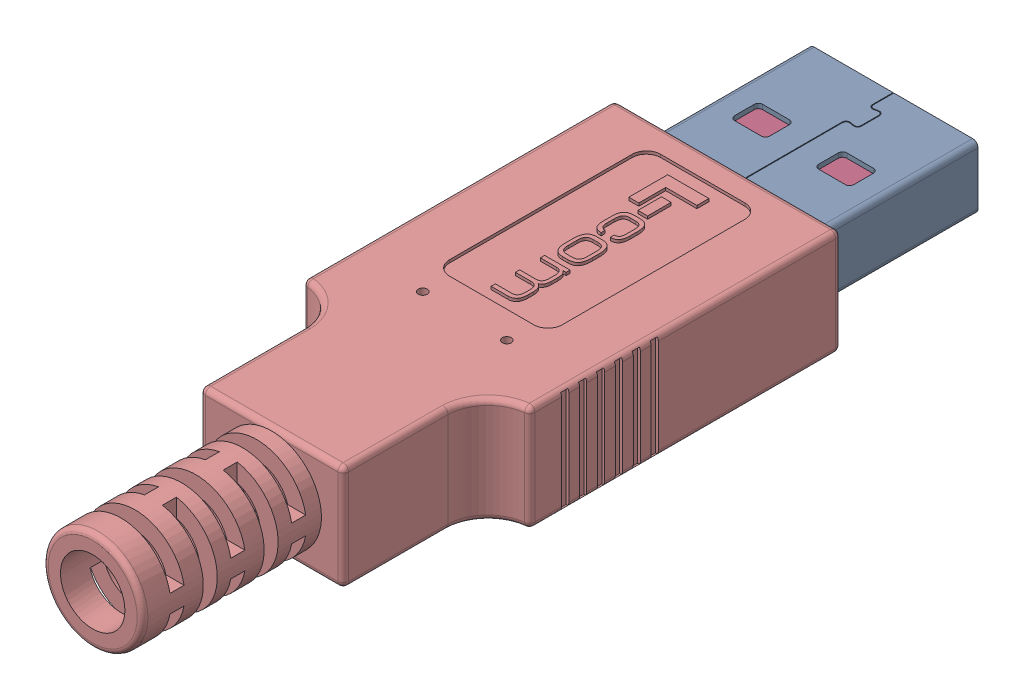
SolidWorks assembly 3AB06-004_ec-comm, configuration Default. Lengths in mm.
Overall size (16.08 7.5 56.9).
10 component instances, 6 part files, 0 mates.
Components (placement in the parent):
- 1AA05-003_1AA05-007-1: 1AA05-003_1AA05-007 [Default] at (0 0 -27.9527) x (-1 0 0) z (0 0 -1) size (12 5.78 36.48)
  - 1AA05-003-MA1-1: 1AA05-003-MA1 [Default] at origin size (12 4.61 36.43)
  - 1AA05-003-MA2_SM CABLE DIA-1: 1AA05-003-MA2_SM CABLE DIA [Default] at (0 0 -16.5) x (-1 0 0) z (0 0 1) size (11.93 5.78 19.5)
  - 1AA05-003-MA3-1: 1AA05-003-MA3 [Default] at (0 0 -8.6) x (-1 0 0) z (0 0 1) size (11.15 3.8 22.3)
  - 1AA05-003-MA4-1: 1AA05-003-MA4 [Default] at (3.5 0.75 -1.6002) x (-1 0 0) z (0 0 1) size (1.27 0.76 18.42)
  - 1AA05-003-MA4-2: 1AA05-003-MA4 [Default] at (1 0.75 -2.667) x (-1 0 0) z (0 0 1) size (1.27 0.76 18.42)
  - 1AA05-003-MA4-3: 1AA05-003-MA4 [Default] at (-1 0.75 -2.667) x (-1 0 0) z (0 0 1) size (1.27 0.76 18.42)
  - 1AA05-003-MA4-4: 1AA05-003-MA4 [Default] at (-3.5 0.75 -1.6002) x (-1 0 0) z (0 0 1) size (1.27 0.76 18.42)
  - 1AA05-003-MA5-1: 1AA05-003-MA5 [Default] at (0 1.85 -22.45) x (-1 0 0) z (0 0 1) size (10.5 3.75 7)
- 3AB06-070_with new logo-1: 3AB06-070_with new logo [Default] at origin size (16.08 7.5 45.09)
